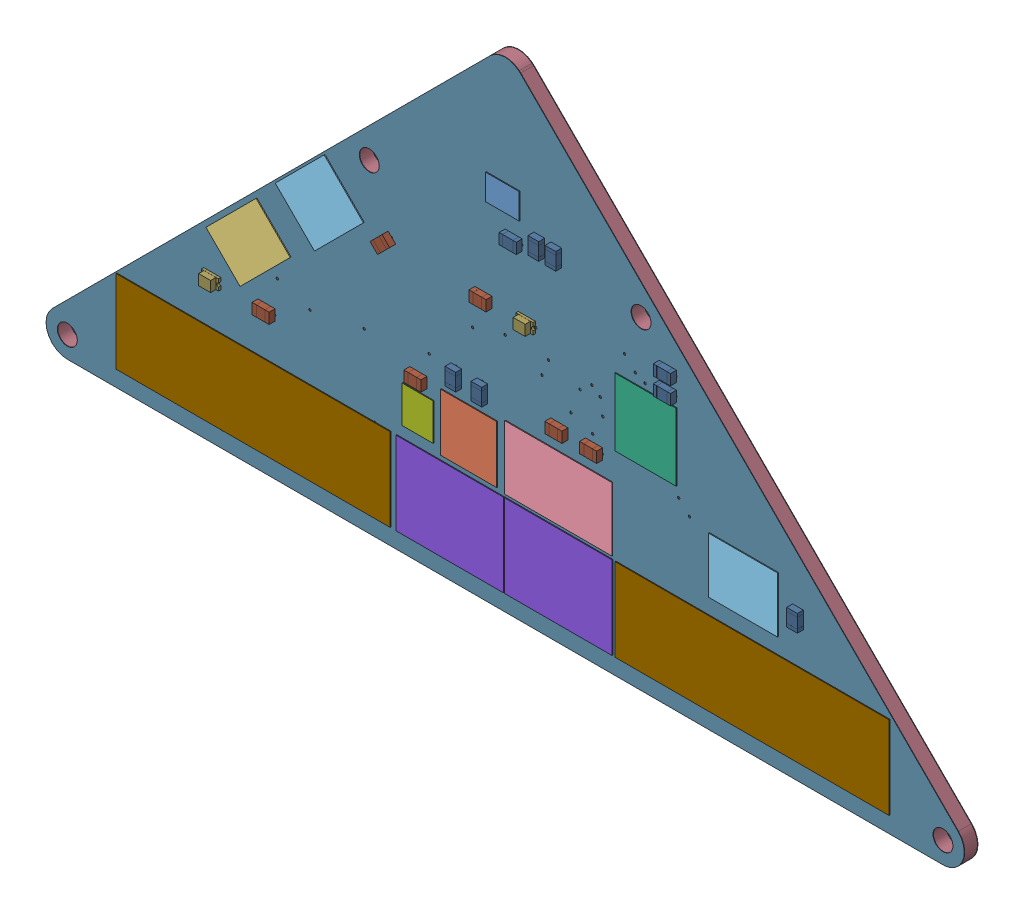
SolidWorks assembly pcb v8-2, configuration Default. Lengths in mm.
Overall size (107.52 56.26 2.5).
33 component instances, 15 part files, 0 mates.
Components (placement in the parent):
- pcb v8-2.step-1: pcb v8-2.step [Default] at origin size (107.52 56.26 2.5)
  - Packages.step-1: Packages.step [Default] at origin size (90.52 41.61 0.9)
    - PQFN50P300X250X97-14N.step-1: PQFN50P300X250X97-14N.step [Default] at (0 -15.24 1.5525) size (3.95 2.99 0.1)
    - AP220533YR13.step-1: AP220533YR13.step [Default] at (-4.191 -41.275 1.5525) x (-1 0 0) z (0 0 1) size (6.6 6.7 0.1)
    - CUS-12B.step-1: CUS-12B.step [Default] at (-30.48 -34.29 1.5525) x (-0.707107 -0.707107 0) z (0 0 1) size (8.3 5.65 0.1)
    - OS102011MS2QS1.step-1: OS102011MS2QS1.step [Default] at (4.318 -41.021 1.5525) size (12.55 7.45 0.1)
    - PTS526SM15SMTR2LFS.step-1: PTS526SM15SMTR2LFS.step [Default] at (27.94 -40.64 1.5525) size (8.1 6.5 0.1)
    - PTS526SM15SMTR2LFS.step-2: PTS526SM15SMTR2LFS.step [Default] at (-21.59 -26.67 1.5525) x (0.707107 0.707107 0) z (0 0 1) size (8.1 6.5 0.1)
    - SOP65P640X120-20N.step-1: SOP65P640X120-20N.step [Default] at (16.51 -30.48 1.5525) x (0 -1 0) z (0 0 1) size (7.9 7.17 0.1)
    - SOT95P285X140-3N.step-1: SOT95P285X140-3N.step [Default] at (-10.16 -42.164 1.5525) x (0 -1 0) z (0 0 1) size (4.3 3.65 0.1)
    - TB00250002BE.step-1: TB00250002BE.step [Default] at (-8.89 -50.8 1.5525) size (12.6 9.7 0.1)
    - TB00250002BE.step-2: TB00250002BE.step [Default] at (3.81 -50.8 1.5525) size (12.6 9.7 0.1)
    - TB00250006BE.step-1: TB00250006BE.step [Default] at (-41.91 -50.8 1.5525) size (32.1 9.7 0.1)
    - TB00250006BE.step-2: TB00250006BE.step [Default] at (16.51 -50.8 1.5525) size (32.1 9.7 0.1)
    - C0805.step-1: C0805.step [Default] at (34.29 -40.64 1.5525) x (0 -1 0) z (0 0 1) size (2 1.25 0.7)
    - C0805.step-2: C0805.step [Default] at (19.05 -25.4 1.5525) size (2 1.25 0.7)
    - C0805.step-3: C0805.step [Default] at (6 -18.08 1.5525) x (0 -1 0) z (0 0 1) size (2 1.25 0.7)
    - C0805.step-4: C0805.step [Default] at (-2.667 -36.195 1.5525) x (0 1 0) z (0 0 1) size (2 1.25 0.7)
    - C0805.step-5: C0805.step [Default] at (19.05 -23.368 1.5525) size (2 1.25 0.7)
    - C0805.step-6: C0805.step [Default] at (4 -18.08 1.5525) x (0 -1 0) z (0 0 1) size (2 1.25 0.7)
    - C0805.step-7: C0805.step [Default] at (-5.715 -36.195 1.5525) x (0 1 0) z (0 0 1) size (2 1.25 0.7)
    - C0805.step-8: C0805.step [Default] at (1 -19.08 1.5525) size (2 1.25 0.7)
    - R0805.step-1: R0805.step [Default] at (-10.16 -38.608 1.5525) x (-1 0 0) z (0 0 1) size (2 1.25 0.7)
    - R0805.step-2: R0805.step [Default] at (-13.97 -26.67 1.5525) x (0.707107 0.707107 0) z (0 0 1) size (2 1.25 0.7)
    - R0805.step-3: R0805.step [Default] at (6.35 -35.56 1.5525) x (-1 0 0) z (0 0 1) size (2 1.25 0.7)
    - R0805.step-4: R0805.step [Default] at (10.414 -35.56 1.5525) x (-1 0 0) z (0 0 1) size (2 1.25 0.7)
    - R0805.step-5: R0805.step [Default] at (-2.54 -26.67 1.5525) x (-1 0 0) z (0 0 1) size (2 1.25 0.7)
    - R0805.step-6: R0805.step [Default] at (-27.94 -40.64 1.5525) size (2 1.25 0.7)
    - CHIP-LED0805.step-1: CHIP-LED0805.step [Default] at (2.54 -26.67 1.5525) x (0 1 0) z (0 0 1) size (1.25 2 0.9)
    - CHIP-LED0805.step-2: CHIP-LED0805.step [Default] at (-34.29 -40.64 1.5525) x (0 -1 0) z (0 0 1) size (1.25 2 0.9)
  - Board.step-1: Board.step [Default] at origin size (107.52 56.26 1.5)
  - 1-soldermask.step-1: 1-soldermask.step [Default] at (0 0 1.5) size (107.52 56.26 0.05)
  - 16-soldermask.step-1: 16-soldermask.step [Default] at origin size (107.52 56.26 0.05)
